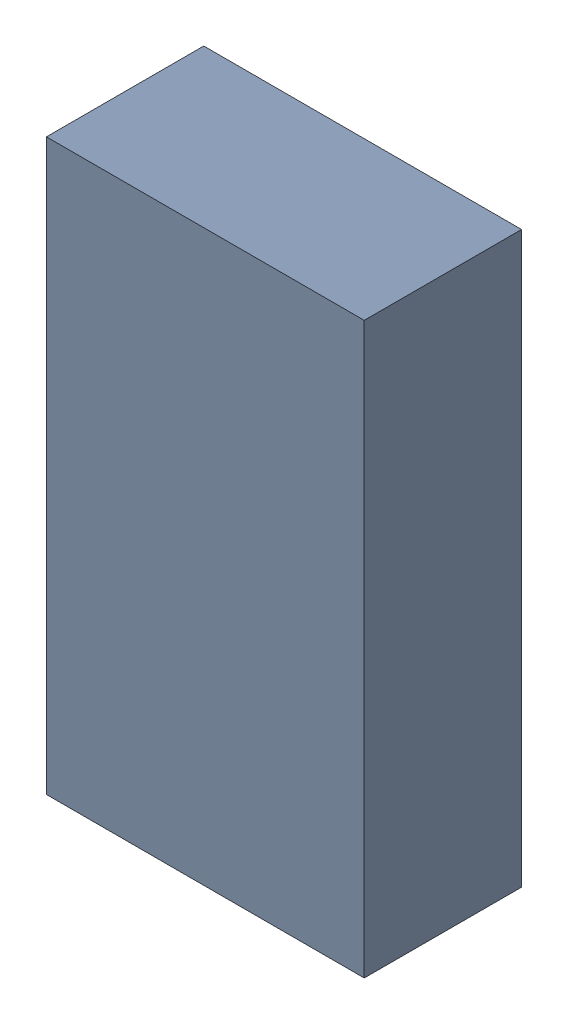
SolidWorks assembly SB16, configuration Default. Lengths in mm.
Overall size (1.01 1.81 0.56).
3 component instances, 2 part files, 0 mates.
Components (placement in the parent):
- 1088884704-1: 1088884704 [Default] at (14.525 12.275 -2.144) size (1.01 1.81 0.5)
  - Extruded-0-1: Extruded-0 [Default] at origin size (1.01 1.81 0.5)
- R0603-1: R0603 [Default] at (14.5251 12.2751 -1.644) x (0 1 0) z (-1 0 0) size (1.7 0.56 0.8)
